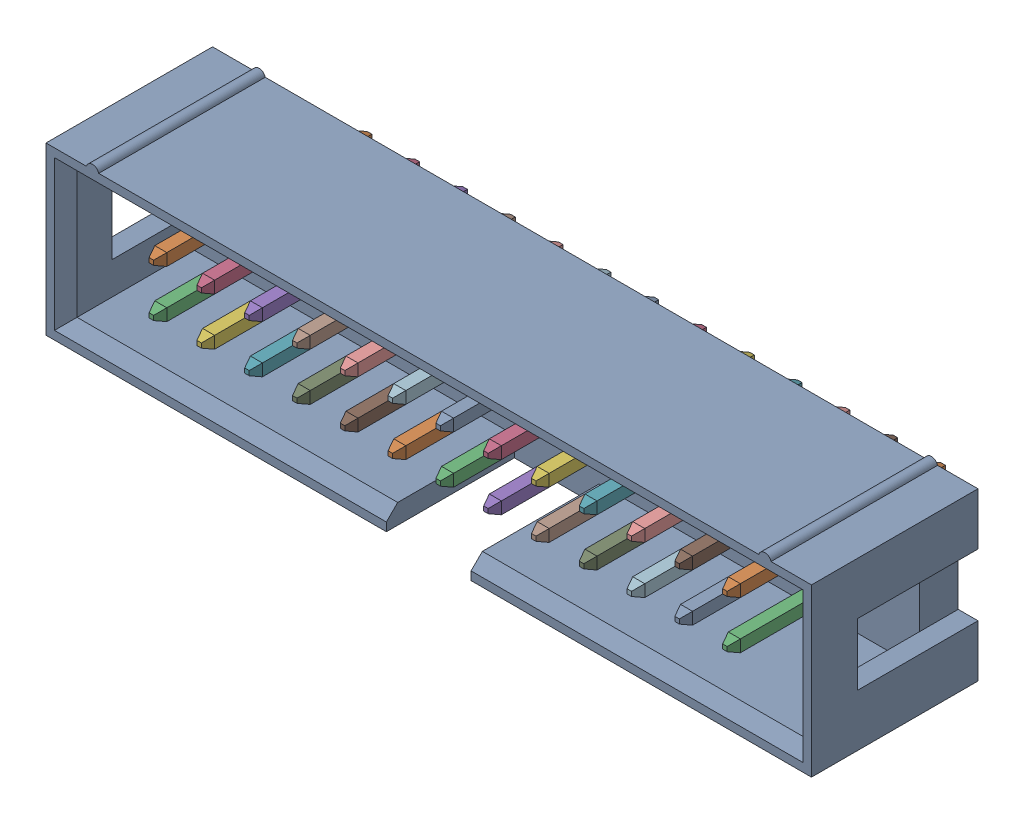
SolidWorks assembly STEP-61202621621-rev1, configuration Default. Lengths in mm.
Overall size (40.68 9.1 12.1).
27 component instances, 2 part files, 0 mates.
Components (placement in the parent):
- 61202621621-1: 61202621621 [Default] at origin size (40.68 9.1 9.1)
- 6120xx21621_PIN-1: 6120xx21621_PIN [Default] at (-15.24 1.27 -1.875) size (0.64 0.64 11.6)
- 6120xx21621_PIN-2: 6120xx21621_PIN [Default] at (-15.24 -1.27 -1.875) size (0.64 0.64 11.6)
- 6120xx21621_PIN-3: 6120xx21621_PIN [Default] at (-12.7 1.27 -1.875) size (0.64 0.64 11.6)
- 6120xx21621_PIN-4: 6120xx21621_PIN [Default] at (-10.16 1.27 -1.875) size (0.64 0.64 11.6)
- 6120xx21621_PIN-5: 6120xx21621_PIN [Default] at (-12.7 -1.27 -1.875) size (0.64 0.64 11.6)
- 6120xx21621_PIN-6: 6120xx21621_PIN [Default] at (-10.16 -1.27 -1.875) size (0.64 0.64 11.6)
- 6120xx21621_PIN-7: 6120xx21621_PIN [Default] at (-7.62 1.27 -1.875) size (0.64 0.64 11.6)
- 6120xx21621_PIN-8: 6120xx21621_PIN [Default] at (-7.62 -1.27 -1.875) size (0.64 0.64 11.6)
- 6120xx21621_PIN-9: 6120xx21621_PIN [Default] at (-5.08 1.27 -1.875) size (0.64 0.64 11.6)
- 6120xx21621_PIN-10: 6120xx21621_PIN [Default] at (-5.08 -1.27 -1.875) size (0.64 0.64 11.6)
- 6120xx21621_PIN-11: 6120xx21621_PIN [Default] at (-2.54 1.27 -1.875) size (0.64 0.64 11.6)
- 6120xx21621_PIN-12: 6120xx21621_PIN [Default] at (0 1.27 -1.875) size (0.64 0.64 11.6)
- 6120xx21621_PIN-13: 6120xx21621_PIN [Default] at (-2.54 -1.27 -1.875) size (0.64 0.64 11.6)
- 6120xx21621_PIN-14: 6120xx21621_PIN [Default] at (0 -1.27 -1.875) size (0.64 0.64 11.6)
- 6120xx21621_PIN-15: 6120xx21621_PIN [Default] at (2.54 1.27 -1.875) size (0.64 0.64 11.6)
- 6120xx21621_PIN-16: 6120xx21621_PIN [Default] at (2.54 -1.27 -1.875) size (0.64 0.64 11.6)
- 6120xx21621_PIN-17: 6120xx21621_PIN [Default] at (5.08 1.27 -1.875) size (0.64 0.64 11.6)
- 6120xx21621_PIN-18: 6120xx21621_PIN [Default] at (7.62 1.27 -1.875) size (0.64 0.64 11.6)
- 6120xx21621_PIN-19: 6120xx21621_PIN [Default] at (5.08 -1.27 -1.875) size (0.64 0.64 11.6)
- 6120xx21621_PIN-20: 6120xx21621_PIN [Default] at (7.62 -1.27 -1.875) size (0.64 0.64 11.6)
- 6120xx21621_PIN-21: 6120xx21621_PIN [Default] at (10.16 1.27 -1.875) size (0.64 0.64 11.6)
- 6120xx21621_PIN-22: 6120xx21621_PIN [Default] at (12.7 1.27 -1.875) size (0.64 0.64 11.6)
- 6120xx21621_PIN-23: 6120xx21621_PIN [Default] at (10.16 -1.27 -1.875) size (0.64 0.64 11.6)
- 6120xx21621_PIN-24: 6120xx21621_PIN [Default] at (12.7 -1.27 -1.875) size (0.64 0.64 11.6)
- 6120xx21621_PIN-25: 6120xx21621_PIN [Default] at (15.24 1.27 -1.875) size (0.64 0.64 11.6)
- 6120xx21621_PIN-26: 6120xx21621_PIN [Default] at (15.24 -1.27 -1.875) size (0.64 0.64 11.6)
